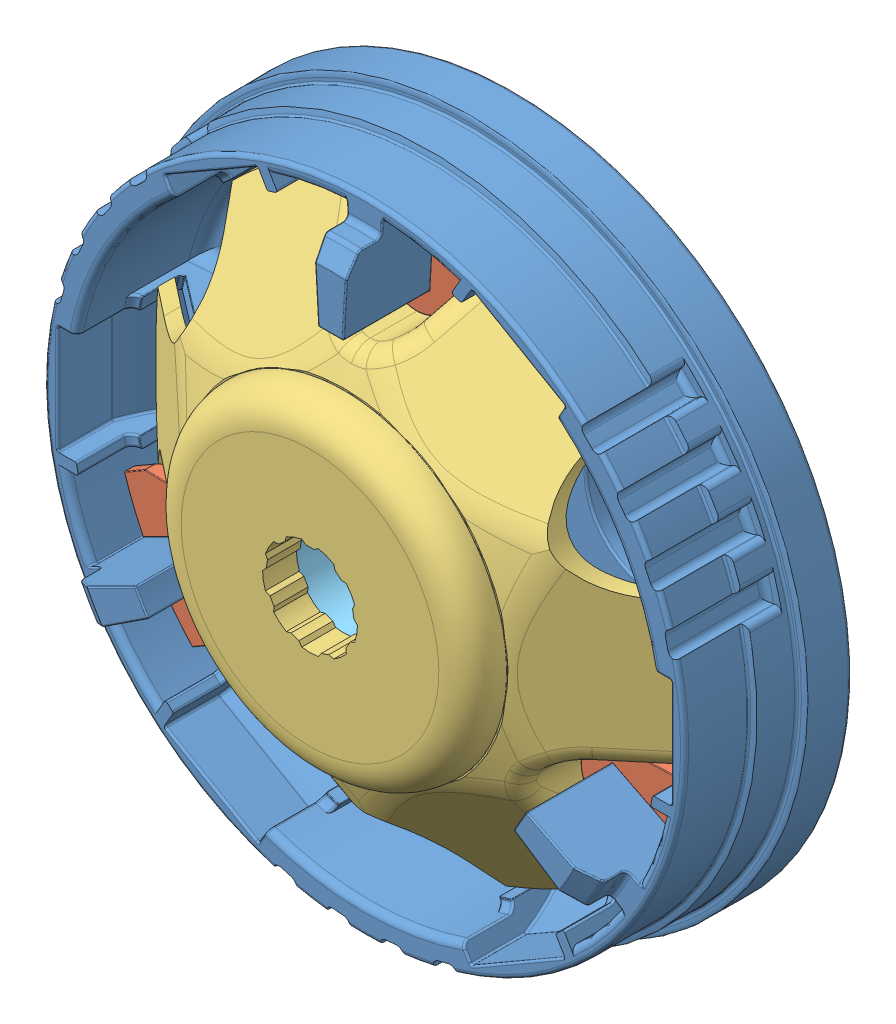
SolidWorks assembly Assembly, configuration Default. Lengths in mm.
Overall size (112.56 113.2 62.79).
13 component instances, 6 part files, 14 mates.
Components (placement in the parent):
- moved half-pulley-1: moved half-pulley [Default] at (9.4238 -28.7365 218.3386) size (101.42 101.42 46.83)
- slider-1: slider [Default] at (48.9282 -51.5444 225.8748) x (0.5 0.866025 0) z (0.866025 -0.5 0) size (20.1 9.79 16.32)
- fixed cover-1: fixed cover [Default] at (9.4238 -28.7365 225.8748) x (0.866025 -0.5 0) z (-0.5 -0.866025 0) size (81.77 25.07 83.5)
- slider-2: slider [Default] at (-30.0805 -51.5444 225.8748) x (0.5 -0.866025 0) z (-0.866025 -0.5 0) size (20.1 9.79 16.32)
- slider-3: slider [Default] at (9.4238 16.8792 225.8748) x (-1 0 0) z (0 1 0) size (20.1 9.79 16.32)
- bushing-1: bushing [Default] at (9.4238 -28.7365 209.3386) size (24 24 34)
- hub-1: hub [Default] at (9.4238 -28.7365 193.3748) x (0.396562 0.918008 0) z (0 0 1) size (20 20 49)
- roller weight-1: roller weight [Default] at (-16.9637 -36.4865 225.8751) x (-0.670794 0 0.741644) z (0 1 0) size (19 19 15.5)
- roller weight-2: roller weight [Default] at (2.9418 -55.4638 225.8751) x (-0.335397 -0.580924 0.741644) z (-0.866025 0.5 0) size (19 19 15.5)
- roller weight-3: roller weight [Default] at (29.3293 -47.7138 225.8751) x (0.335397 -0.580924 0.741644) z (-0.866025 -0.5 0) size (19 19 15.5)
- roller weight-4: roller weight [Default] at (35.8113 -20.9865 225.8751) x (0.670794 0 0.741644) z (0 -1 0) size (19 19 15.5)
- roller weight-5: roller weight [Default] at (15.9059 -2.0093 225.8751) x (0.335397 0.580924 0.741644) z (0.866025 -0.5 0) size (19 19 15.5)
- roller weight-6: roller weight [Default] at (-10.4816 -9.7593 225.8751) x (-0.335397 0.580924 0.741644) z (0.866025 0.5 0) size (19 19 15.5)
Mates (geometry in assembly coordinates):
- Parallelo1: parallel anti-aligned: plane of slider-1 through (30.8397 -46.8745 222.8748) normal (-0.5 -0.866025 0); plane of fixed cover-1 through (36.1522 -49.9417 225.8748) normal (0.5 0.866025 0)
- Concentrico1: concentric anti-aligned: cylinder of slider-1 through (38.6522 -45.6115 227.8748) axis (0 0 -1) radius 5; cylinder of fixed cover-1 through (38.6522 -45.6115 225.8748) axis (0 0 1) radius 5
- Parallelo6: parallel anti-aligned: plane of slider-1 through (30.8397 -46.8745 222.8748) normal (0 0 1); plane of fixed cover-1 through (36.1522 -49.9417 222.8748) normal (0 0 -1)
- Parallelo5: parallel anti-aligned: plane of moved half-pulley-1 through (-26.7214 -52.4869 212.8386) normal (0.549143 -0.835729 0); plane of slider-2 through (-28.3115 -53.527 218.8748) normal (-0.549143 0.835729 0)
- Concentrico2: concentric aligned: cylinder of moved half-pulley-1 through (9.4238 -28.7365 209.3386) axis (0 0 1) radius 12; cylinder of fixed cover-1 through (9.4238 -28.7365 225.8748) axis (0 0 1) radius 7
- Concentrico3: concentric anti-aligned: cylinder of moved half-pulley-1 through (9.4238 -28.7365 209.3386) axis (0 0 1) radius 12; cylinder of bushing-1 through (9.4238 -28.7365 243.3386) axis (0 0 -1) radius 12
- Concentrico4: concentric aligned: cylinder of bushing-1 through (9.4238 -28.7365 243.3386) axis (0 0 -1) radius 10; cylinder of hub-1 through (9.4238 -28.7365 242.3748) axis (0 0 -1) radius 10
- Distanza2: distance = 0.25 mm anti-aligned: plane of roller weight-1 through (-16.9637 -20.9865 225.8751) normal (0 1 0); plane of moved half-pulley-1 through (9.4238 -20.7365 218.3386) normal (0 -1 0)
- AccoppiaPercorso3: path: point of ?; curve of moved half-pulley-1
- Tangente1: tangent anti-aligned: plane of fixed cover-1 through (-6.5424 -28.7365 246.1644) normal (0.618405 0 -0.78586); cylinder of roller weight-1 through (-16.9637 -20.9865 225.8751) axis (0 -1 0) radius 9.5
- Coincidente1: coincident aligned: plane of moved half-pulley-1 through (9.4238 -28.7365 209.3386) normal (0 0 -1); plane of bushing-1 through (9.4238 -28.7365 209.3386) normal (0 0 -1)
- Coincidente2: coincident anti-aligned: plane of fixed cover-1 through (9.4238 -28.7365 242.3748) normal (0 0 -1); plane of hub-1 through (9.4238 -28.7365 242.3748) normal (0 0 1)
- Coincidente4: coincident anti-aligned: plane of slider-1 through (30.8397 -46.8745 222.8748) normal (-0.5 -0.866025 0); plane of fixed cover-1 through (36.1522 -49.9417 225.8748) normal (0.5 0.866025 0)
- Coincidente5: coincident anti-aligned: plane of slider-1 through (30.8397 -46.8745 222.8748) normal (0 0 1); plane of fixed cover-1 through (36.1522 -49.9417 222.8748) normal (0 0 -1)
